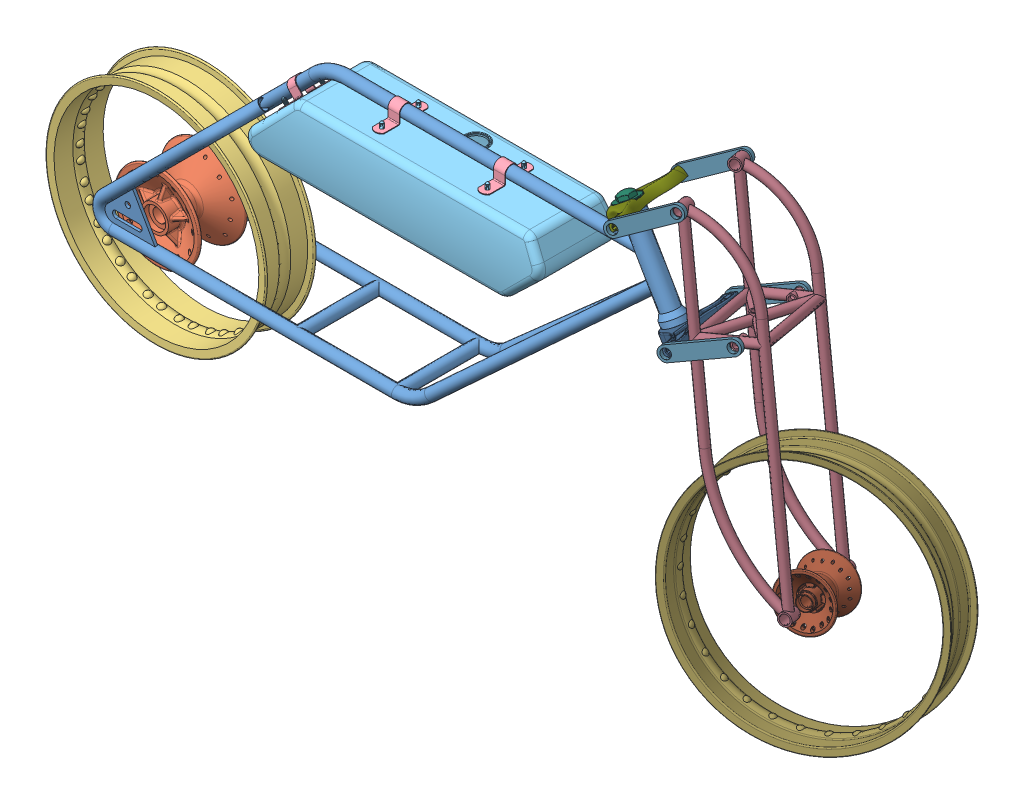
SolidWorks assembly motorcycle, configuration Default. Lengths in mm.
Overall size (1988.96 1015.88 498.07).
33 component instances, 16 part files, 40 mates.
Components (placement in the parent):
- chassis-1: chassis [Default] at (10.1216 403.4591 1154.508) x (0 0 -1) z (1 0 0) size (205.4 616.68 1328.04)
- hub-1: hub [Default] at (-665.404 330.5356 1154.508) x (0 0 -1) z (-0.189398 -0.9819 0) size (115 188.67 188.67)
- rim-1: rim [Default] at (-665.404 330.5356 1154.508) x (0 0 -1) z (-0.189398 -0.9819 0) size (111.16 485.06 485.06)
- clamp-4: clamp [Default] at (-400.2858 664.7675 1154.508) x (0 0 -1) z (0.707107 0.707107 0) size (110 34.5 25)
- fuel tank-2: fuel tank [Default] at (-131.5942 583.4591 1154.508) size (649.82 165 180)
- clamp-5: clamp [Default] at (-196.0942 733.4591 1154.508) x (0 0 -1) z (1 0 0) size (110 34.5 25)
- clamp-6: clamp [Default] at (35.9058 733.4591 1154.508) x (0 0 -1) z (1 0 0) size (110 34.5 25)
- bearing-1: bearing [Default] at (536.276 649.8635 1141.0551) x (0.030157 -0.873291 -0.486265) z (-0.954581 0.119108 -0.27311) size (49.19 58.89 47.57)
  - cone-1: cone [Default] at (-15.9296 43.6646 111.8092) x (-0.289818 0.956042 0.044598) z (-0.566562 -0.133821 -0.81308) size (43 8 43)
  - ball-2: ball [Default] at (-17.254 35.2993 95.8513) size (6 6 6)
  - ball-3: ball [Default] at (-14.145 61.6423 111.8244) size (6 6 6)
  - ball-4: ball [Default] at (-5.5438 29.2173 108.6796) size (6 6 6)
  - ball-5: ball [Default] at (-19.3302 59.6057 104.0182) size (6 6 6)
  - ball-6: ball [Default] at (-21.952 53.0098 97.569) size (6 6 6)
  - ball-8: ball [Default] at (-2.9607 51.1039 121.9506) x (0.87527 0.100433 -0.473091) z (0.470861 0.046372 0.880988) size (6 6 6)
  - ball-9: ball [Default] at (-8.0427 58.4729 118.5094) x (0.691864 -0.046109 0.720554) z (-0.358402 -0.888263 0.287292) size (6 6 6)
  - ball-10: ball [Default] at (-0.5125 41.8747 121.0555) x (0.771623 0.187035 0.60796) z (-0.536531 -0.322008 0.780029) size (6 6 6)
  - ball-14: ball [Default] at (-1.4755 33.7157 116.1082) size (6 6 6)
  - ball-15: ball [Default] at (-11.4258 29.8076 101.1281) size (6 6 6)
  - cup-1: cup [Default] at (-14.993 43.9814 111.1044) x (-0.512767 -0.285371 -0.809712) z (0.376905 -0.922219 0.086339) size (46.6 10.02 46.6)
  - guide-2: guide [Default] at (-13.8019 44.3843 110.2081) x (0.409171 -0.901908 0.138349) z (0.487408 0.344218 0.802463) size (42.29 6.43 42.29)
  - ball-16: ball [Default] at (-21.178 43.9487 94.5245) x (0.87527 0.100433 -0.473091) z (0.470861 0.046372 0.880988) size (6 6 6)
- triple tee-1: triple tee [Default] at (436.7869 640.6826 1150.554) x (0.318277 0.183757 0.930018) z (-0.5 0.866025 0) size (230 86.81 240.14)
- front wheel.-1: front wheel. [Default] at (865.3486 296.6574 1185.679) x (-0.318277 -0.183757 -0.930018) z (0.919521 0.178806 -0.350014) size (230 940.8 510.67)
  - hubfront-1: hubfront [Default] at (36.1103 10.4626 -130.5419) size (90 113.34 113.34)
  - rimfront-1: rimfront [Default] at (105.8511 10.4626 -130.5419) size (96.75 510.67 510.67)
  - front girder-1: front girder [Default] at (205.8511 283.2262 -250.5419) size (230 698.16 145.4)
- linkage-1: linkage [Default] at (476.7885 654.3622 1009.4327) x (-0.318277 -0.183757 -0.930018) z (0.865896 0.343004 -0.364105) size (10 30 150)
- linkage-2: linkage [Default] at (553.8115 698.8315 1234.497) x (-0.318277 -0.183757 -0.930018) z (0.865896 0.343004 -0.364105) size (10 30 150)
- triple tee nut-1: triple tee nut [Default] at (313.1216 834.8655 1154.508) x (0.031059 0.017932 0.999357) z (-0.865468 -0.499678 0.035864) size (54 29.51 54)
- triple teeup-1: triple teeup [Default] at (292.3072 796.5156 1169.2086) x (0.318277 0.183757 0.930018) z (-0.805419 -0.465009 0.367515) size (230.01 21.64 88.32)
- linkage-4: linkage [Default] at (358.6452 843.2879 1012.5356) x (-0.318277 -0.183757 -0.930018) z (0.802598 0.469865 -0.367509) size (10 30 150)
- linkage-5: linkage [Default] at (432.4855 885.9196 1228.2998) x (0.318277 0.183757 0.930018) z (-0.802598 -0.469865 0.367509) size (10 30 150)
Mates (geometry in assembly coordinates):
- Concentric2: concentric aligned: cylinder of hub-1 through (-665.404 330.5356 1101.008) axis (0 0 -1) radius 15; cylinder of rim-1 through (-665.404 330.5356 1154.508) axis (0 0 -1) radius 225.1
- Width1: width anti-aligned: plane of chassis-1 through (-168.8981 544.2251 1067.508) normal (0 0 1); plane of chassis-1 through (-168.8981 544.2251 1241.508) normal (0 0 -1); plane of hub-1 through (-665.404 330.5356 1101.008) normal (0 0 -1); plane of hub-1 through (-665.404 330.5356 1208.008) normal (0 0 1)
- Concentric3: concentric aligned: cylinder of chassis-1 through (-665.404 330.5356 1079.508) axis (0 0 -1) radius 7.5; cylinder of hub-1 through (-665.404 330.5356 1101.008) axis (0 0 -1) radius 15
- Width3: width anti-aligned: plane of chassis-1 through (-168.8981 544.2251 1067.508) normal (0 0 1); plane of chassis-1 through (-168.8981 544.2251 1241.508) normal (0 0 -1); plane of rim-1; plane of rim-1
- Concentric25: concentric aligned: cylinder of clamp-4 through (-392.5076 674.6669 1114.508) axis (0.707107 -0.707107 0) radius 4; cylinder of fuel tank-2 through (-402.0536 684.2129 1114.508) axis (0.707107 -0.707107 0) radius 3.5
- Concentric26: concentric aligned: cylinder of clamp-4 through (-392.5076 674.6669 1194.508) axis (0.707107 -0.707107 0) radius 4; cylinder of fuel tank-2 through (-402.0536 684.2129 1194.508) axis (0.707107 -0.707107 0) radius 3.5
- Concentric27: concentric anti-aligned: cylinder of chassis-1 through (-495.4419 597.8956 1154.508) axis (0.707107 0.707107 0) radius 12.7; cylinder of clamp-4 through (-396.7503 696.5873 1154.508) axis (-0.707107 -0.707107 0) radius 13
- Concentric28: concentric aligned: cylinder of fuel tank-2 through (-183.5942 748.4591 1114.508) axis (0 -1 0) radius 3.5; cylinder of clamp-5 through (-183.5942 734.9591 1114.508) axis (0 -1 0) radius 4
- Concentric29: concentric aligned: cylinder of fuel tank-2 through (-183.5942 748.4591 1194.508) axis (0 -1 0) radius 3.5; cylinder of clamp-5 through (-183.5942 734.9591 1194.508) axis (0 -1 0) radius 4
- Concentric30: concentric aligned: line of chassis-1 through (360.1216 753.4591 1154.508) axis (-1 0 0); cylinder of clamp-5 through (-171.0942 753.4591 1154.508) axis (-1 0 0) radius 13
- Coincident8: coincident anti-aligned: plane of fuel tank-2 through (-131.5942 733.4591 1154.508) normal (0 1 0); plane of clamp-5 through (-171.0942 733.4591 1138.008) normal (0 -1 0)
- Coincident9: coincident anti-aligned: plane of clamp-4 through (-382.6081 682.4451 1138.008) normal (0.707107 -0.707107 0); plane of fuel tank-2 through (-481.5942 583.4591 1244.508) normal (-0.707107 0.707107 0)
- Concentric31: concentric aligned: cylinder of fuel tank-2 through (48.4058 748.4591 1114.508) axis (0 -1 0) radius 3.5; cylinder of clamp-6 through (48.4058 734.9591 1114.508) axis (0 -1 0) radius 4
- Concentric32: concentric aligned: cylinder of fuel tank-2 through (48.4058 748.4591 1194.508) axis (0 -1 0) radius 3.5; cylinder of clamp-6 through (48.4058 734.9591 1194.508) axis (0 -1 0) radius 4
- Concentric33: concentric aligned: line of chassis-1 through (360.1216 753.4591 1154.508) axis (-1 0 0); cylinder of clamp-6 through (60.9058 753.4591 1154.508) axis (-1 0 0) radius 13
- Coincident10: coincident anti-aligned: plane of chassis-1 through (416.1216 656.4643 1154.508) normal (0.5 -0.866025 0); plane of bearing-1/cone-1 through (419.9707 658.6865 1143.9016) normal (-0.5 0.866025 0)
- Concentric34: concentric anti-aligned: cylinder of chassis-1 through (337.6216 792.4302 1154.508) axis (0.5 -0.866025 0) radius 15.875; cylinder of bearing-1/cone-1 through (416.1216 656.4643 1154.508) axis (-0.5 0.866025 0) radius 11.5
- Concentric40: concentric aligned: cylinder of front wheel.-1/front girder-1 through (591.1245 710.9588 1169.8699) axis (0.318277 0.183757 0.930018) radius 6; cylinder of linkage-1 through (525.5595 673.1048 978.2862) axis (0.318277 0.183757 0.930018) radius 10
- Concentric42: concentric anti-aligned: cylinder of front wheel.-1/front girder-1 through (540.2002 681.5577 1021.067) axis (-0.318277 -0.183757 -0.930018) radius 6; cylinder of linkage-2 through (602.5825 717.5741 1203.3505) axis (0.318277 0.183757 0.930018) radius 10
- Concentric44: concentric aligned: cylinder of chassis-1 through (337.6216 792.4302 1154.508) axis (0.5 -0.866025 0) radius 15.875; cylinder of triple tee-1 through (313.1216 834.8655 1154.508) axis (0.5 -0.866025 0) radius 15
- Distance5: distance = 2 mm anti-aligned: plane of chassis-1 through (443.688 658.5233 1154.508) normal (0.5 -0.866025 0); plane of triple tee-1 through (429.703 648.1397 1033.2276) normal (-0.5 0.866025 0)
- Concentric45: concentric anti-aligned: cylinder of triple tee-1 through (313.1216 834.8655 1154.508) axis (0.5 -0.866025 0) radius 15; cylinder of triple tee nut-1 through (308.3716 843.0927 1154.508) axis (-0.5 0.866025 0) radius 18
- Screw2: screw = 1 anti-aligned: cylinder of triple tee nut-1 through (308.3716 843.0927 1154.508) axis (-0.5 0.866025 0) radius 15; cylinder of triple tee-1 through (313.1216 834.8655 1154.508) axis (0.5 -0.866025 0) radius 15
- LimitDistance1: limit distance = 6 mm anti-aligned: plane of triple tee nut-1 through (310.1216 840.0616 1154.508) normal (0.5 -0.866025 0); plane of triple tee-1 through (313.1216 834.8655 1154.508) normal (-0.5 0.866025 0)
- Concentric46: concentric anti-aligned: cylinder of triple tee-1 through (431.5185 637.6409 1050.8094) axis (-0.318277 -0.183757 -0.930018) radius 5; cylinder of linkage-1 through (421.6519 631.9444 1021.9788) axis (0.318277 0.183757 0.930018) radius 10
- Distance6: distance = 1 mm anti-aligned: plane of linkage-1 through (476.7885 654.3622 1009.4327) normal (0.318277 0.183757 0.930018); plane of triple tee-1 through (428.1116 647.2209 1028.5775) normal (-0.318277 -0.183757 -0.930018)
- Concentric47: concentric aligned: cylinder of triple tee-1 through (491.9912 672.5548 1227.5127) axis (0.318277 0.183757 0.930018) radius 5; cylinder of linkage-2 through (498.675 676.4137 1247.0431) axis (0.318277 0.183757 0.930018) radius 10
- Distance7: distance = 1 mm anti-aligned: plane of triple tee-1 through (501.3153 689.4851 1242.4816) normal (0.318277 0.183757 0.930018); plane of linkage-2 through (550.6287 696.9939 1225.1968) normal (-0.318277 -0.183757 -0.930018)
- Concentric48: concentric anti-aligned: cylinder of front wheel.-1/front girder-1 through (540.2002 681.5577 1021.067) axis (-0.318277 -0.183757 -0.930018) radius 6; cylinder of linkage-1 through (525.5595 673.1048 978.2862) axis (0.318277 0.183757 0.930018) radius 10
- Concentric49: concentric aligned: cylinder of front wheel.-1/front girder-1 through (591.1245 710.9588 1169.8699) axis (0.318277 0.183757 0.930018) radius 6; cylinder of linkage-2 through (602.5825 717.5741 1203.3505) axis (0.318277 0.183757 0.930018) radius 10
- Distance8: distance = 1 mm anti-aligned: plane of front wheel.-1/front girder-1 through (529.0605 675.1262 988.5164) normal (-0.318277 -0.183757 -0.930018); plane of linkage-1 through (476.7885 654.3622 1009.4327) normal (0.318277 0.183757 0.930018)
- Concentric50: concentric aligned: cylinder of triple tee-1 through (313.1216 834.8655 1154.508) axis (0.5 -0.866025 0) radius 15; cylinder of triple teeup-1 through (314.0541 833.2503 1154.508) axis (0.5 -0.866025 0) radius 15
- Distance10: distance = 0.5 mm anti-aligned: plane of triple tee nut-1 through (293.4063 815.0481 1155.4763) normal (0.5 -0.866025 0); plane of triple teeup-1 through (317.0239 828.1064 1154.508) normal (-0.5 0.866025 0)
- Concentric51: concentric anti-aligned: cylinder of triple teeup-1 through (317.1731 818.9549 1054.1165) axis (-0.318277 -0.183757 -0.930018) radius 6; cylinder of linkage-4 through (307.3066 813.2584 1025.286) axis (0.318277 0.183757 0.930018) radius 10
- Concentric52: concentric aligned: cylinder of front wheel.-1/front girder-1 through (407.1194 871.6636 991.4151) axis (0.318277 0.183757 0.930018) radius 9.7; cylinder of linkage-4 through (403.6183 869.6423 981.1849) axis (0.318277 0.183757 0.930018) radius 10
- Distance11: distance = 1 mm anti-aligned: plane of linkage-4 through (358.6452 843.2879 1012.5356) normal (0.318277 0.183757 0.930018); plane of triple teeup-1 through (299.1122 816.1877 1039.3393) normal (-0.318277 -0.183757 -0.930018)
- Distance12: distance = 1 mm anti-aligned: plane of linkage-5 through (432.4855 885.9196 1228.2998) normal (-0.318277 -0.183757 -0.930018); plane of triple teeup-1 through (372.4398 858.5234 1253.1868) normal (0.318277 0.183757 0.930018)
- Concentric53: concentric anti-aligned: cylinder of triple teeup-1 through (377.6458 853.8688 1230.8199) axis (0.318277 0.183757 0.930018) radius 6; cylinder of linkage-5 through (387.5124 859.5653 1259.6505) axis (-0.318277 -0.183757 -0.930018) radius 10
- Concentric54: concentric aligned: cylinder of front wheel.-1/front girder-1 through (480.3231 913.9278 1205.3192) axis (-0.318277 -0.183757 -0.930018) radius 9.7; cylinder of linkage-5 through (483.8242 915.9491 1215.5494) axis (-0.318277 -0.183757 -0.930018) radius 10
- Lock1: lock: unknown of triple tee-1; unknown of triple teeup-1
